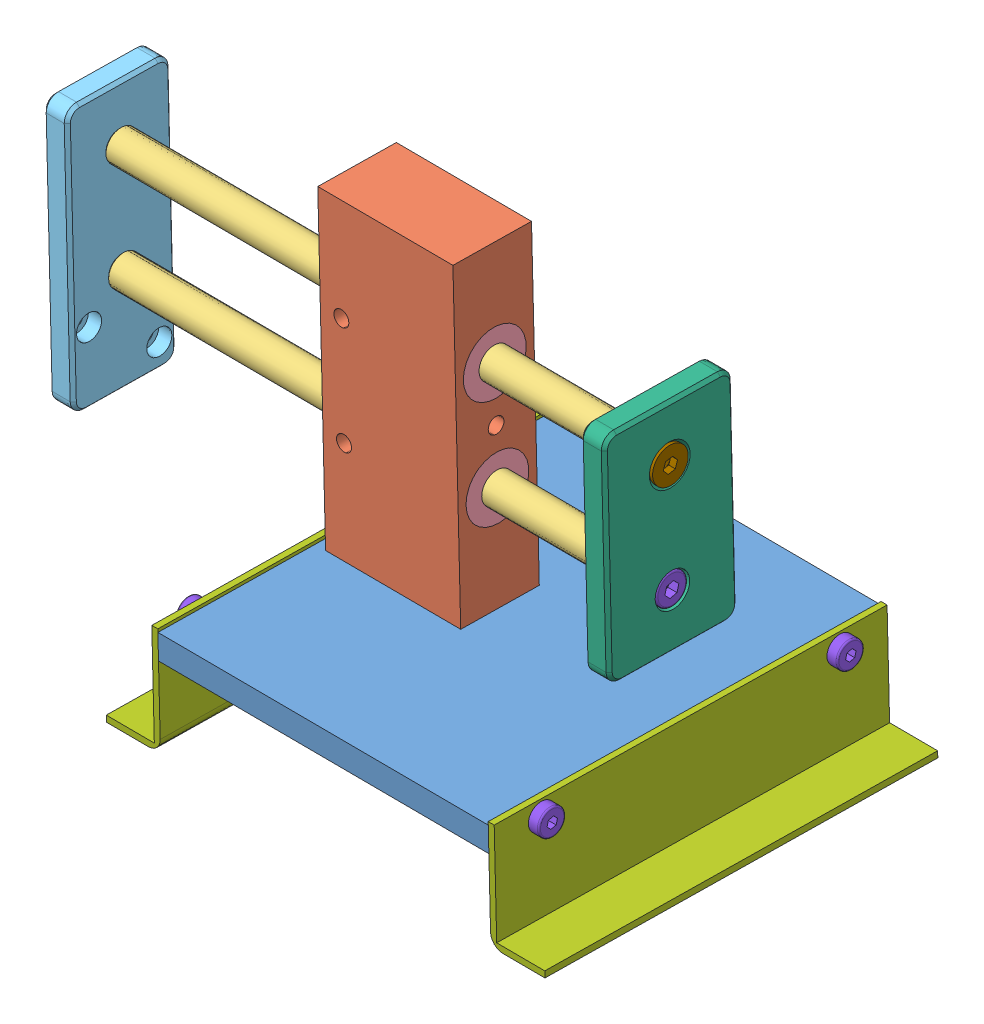
SolidWorks assembly cum s1, configuration Default. Lengths in mm.
Overall size (216.07 137.7 128.52).
22 component instances, 9 part files, 48 mates.
Components (placement in the parent):
- tam de lon-1: tam de lon [Default] at (119.0958 51.1975 54.0073) x (-0.999587 -0.017639 -0.022689) z (-0.022562 -0.007384 0.999718) size (110 8 125)
- con truot s1-2: con truot s1 [Default] at (88.5768 136.6703 53.9498) x (0.999587 0.017639 0.022689) z (0.022562 0.007384 -0.999718) size (45 102 25)
- chot dan huong-1: chot dan huong [Default] at (-13.3094 117.3701 51.5078) x (0.021471 -0.983136 -0.181614) z (-0.019103 -0.182026 0.983108) size (10 175 10)
- chot dan huong-2: chot dan huong [Default] at (-12.6864 82.3765 51.2634) x (0.026236 -0.237789 -0.970963) z (0.011731 -0.971157 0.238153) size (10 175 10)
- bac lot-1: bac lot [Default] at (66.3976 118.7766 53.3171) x (0.028076 -0.767933 -0.639915) z (-0.006137 -0.640287 0.768111) size (20 12 20)
- bac lot-2: bac lot [Default] at (67.0207 83.783 53.0727) x (0.018145 -0.999587 -0.022287) z (-0.022287 -0.022689 0.999494) size (20 12 20)
- bac lot-3: bac lot [Default] at (111.379 119.5704 54.3381) x (-0.014484 -0.372719 0.927831) z (0.024823 -0.927776 -0.37231) size (20 12 20)
- bac lot-4: bac lot [Default] at (112.0021 84.5768 54.0937) x (-0.014484 -0.372719 0.927831) z (0.024823 -0.927776 -0.37231) size (20 12 20)
- ban canh truoc-1: ban canh truoc [Default] at (-12.8555 91.8747 51.3298) x (-0.022562 -0.007384 0.999718) z (0.017801 -0.999817 -0.006983) size (33 8 86)
- ban canh sau -S1-1: ban canh sau -S1 [Default] at (161.9298 102.9601 55.3563) x (-0.022562 -0.007384 0.999718) z (-0.017801 0.999817 0.006983) size (41 8 70)
- khoi do-1: khoi do [Default] at (173.7917 36.5109 117.6508) x (0.022562 0.007384 -0.999718) z (-0.999587 -0.017639 -0.022689) size (125 35 18)
- khoi do-2: khoi do [Default] at (64.9414 35.4633 -9.8487) x (-0.022562 -0.007384 0.999718) z (0.999587 0.017639 0.022689) size (125 35 18)
- socket head thin cap screw_din-2: socket head thin cap screw_din [DIN 7984 - M5 x 12 --- 9.6N] at (57.6203 45.7804 100.0932) x (0.999587 0.017639 0.022689) z (-0.022689 -0.0002 0.999743) size (15.5 8.5 8.5)
- socket head thin cap screw_din-3: socket head thin cap screw_din [DIN 7984 - M5 x 12 --- 9.6N] at (59.7637 46.4818 5.12) x (0.999587 0.017639 0.022689) z (-0.022689 -0.0002 0.999743) size (15.5 8.5 8.5)
- socket head thin cap screw_din-4: socket head thin cap screw_din [DIN 7984 - M5 x 12 --- 9.6N] at (180.7137 48.6161 7.8654) x (-0.999587 -0.017639 -0.022689) z (0.022689 -0.968916 -0.246346) size (15.5 8.5 8.5)
- socket head thin cap screw_din-5: socket head thin cap screw_din [DIN 7984 - M5 x 12 --- 9.6N] at (178.5703 47.9147 102.8386) x (-0.999587 -0.017639 -0.022689) z (0.022689 -0.968916 -0.246346) size (15.5 8.5 8.5)
- socket head thin cap screw_din-6: socket head thin cap screw_din [DIN 7984 - M5 x 12 --- 9.6N] at (108.0343 45.1492 61.2151) x (-0.017801 0.999817 0.006983) z (-0.006983 -0.007108 0.99995) size (15.5 8.5 8.5)
- socket head thin cap screw_din-7: socket head thin cap screw_din [DIN 7984 - M5 x 12 --- 9.6N] at (72.3876 44.6249 45.4025) x (-0.017801 0.999817 0.006983) z (-0.006983 -0.007108 0.99995) size (15.5 8.5 8.5)
- socket head thin cap screw_din-9: socket head thin cap screw_din [DIN 7984 - M6 x 14 --- 11N] at (170.0381 85.6009 55.411) x (-0.999587 -0.017639 -0.022689) z (0.022689 -0.968916 -0.246346) size (18 10 10)
- socket head thin cap screw_din-10: socket head thin cap screw_din [DIN 7984 - M6 x 14 --- 11N] at (-20.4831 82.2389 51.0864) x (0.999587 0.017639 0.022689) z (-0.022689 -0.0002 0.999743) size (18 10 10)
- socket csink head cap screw 10642_din-2: socket csink head cap screw 10642_din [EN ISO 10642 - M6 x 16 - 16N] at (-21.526 117.2251 51.3213) x (0.999587 0.017639 0.022689) z (-0.022678 -0.000819 0.999742) size (16 11.34 11.34)
- socket csink head cap screw 10642_din-3: socket csink head cap screw 10642_din [EN ISO 10642 - M6 x 16 - 16N] at (169.8349 120.6019 55.665) x (-0.999587 -0.017639 -0.022689) z (0.021761 -0.980227 -0.196676) size (16 11.34 11.34)
Mates (geometry in assembly coordinates):
- Parallel5: parallel anti-aligned: plane of tam de lon-1 through (119.0958 51.1975 54.0073) normal (-0.017801 0.999817 0.006983); plane of con truot s1-2 through (90.1077 50.686 53.3493) normal (0.017801 -0.999817 -0.006983)
- Parallel6: parallel anti-aligned: plane of tam de lon-1 through (172.8053 43.7076 117.6817) normal (-0.022562 -0.007384 0.999718); plane of con truot s1-2 through (67.6142 66.3785 40.454) normal (0.022562 0.007384 -0.999718)
- Concentric3: concentric aligned: cylinder of tam de lon-1 through (72.2844 50.4239 45.443) axis (0.017801 -0.999817 -0.006983) radius 2.75; circle of con truot s1-2
- Coincident1: coincident anti-aligned: plane of tam de lon-1 through (119.0958 51.1975 54.0073) normal (-0.017801 0.999817 0.006983); plane of con truot s1-2 through (90.1077 50.686 53.3493) normal (0.017801 -0.999817 -0.006983)
- Concentric4: concentric anti-aligned: cylinder of con truot s1-2 through (41.408 118.3356 52.7498) axis (0.999587 0.017639 0.022689) radius 6; cylinder of chot dan huong-1 through (259.5778 122.1855 57.702) axis (-0.999587 -0.017639 -0.022689) radius 5
- Concentric5: concentric anti-aligned: cylinder of con truot s1-2 through (42.031 83.342 52.5054) axis (0.999587 0.017639 0.022689) radius 6; cylinder of chot dan huong-2 through (260.2009 87.1919 57.4576) axis (-0.999587 -0.017639 -0.022689) radius 5
- Concentric6: concentric anti-aligned: cylinder of con truot s1-2 through (41.408 118.3356 52.7498) axis (0.999587 0.017639 0.022689) radius 6; cylinder of bac lot-1 through (78.3927 118.9883 53.5893) axis (-0.999587 -0.017639 -0.022689) radius 6
- Coincident2: coincident anti-aligned: plane of con truot s1-2 through (68.3968 118.8119 53.3624) normal (-0.999587 -0.017639 -0.022689); plane of bac lot-1 through (68.3968 118.8119 53.3624) normal (0.999587 0.017639 0.022689)
- Concentric7: concentric anti-aligned: cylinder of con truot s1-2 through (42.031 83.342 52.5054) axis (0.999587 0.017639 0.022689) radius 6; cylinder of bac lot-2 through (79.0157 83.9947 53.3449) axis (-0.999587 -0.017639 -0.022689) radius 6
- Coincident3: coincident anti-aligned: plane of con truot s1-2 through (69.0199 83.8183 53.1181) normal (-0.999587 -0.017639 -0.022689); plane of bac lot-2 through (69.0199 83.8183 53.1181) normal (0.999587 0.017639 0.022689)
- Concentric8: concentric aligned: cylinder of con truot s1-2 through (41.408 118.3356 52.7498) axis (0.999587 0.017639 0.022689) radius 6; cylinder of bac lot-3 through (99.384 119.3587 54.0658) axis (0.999587 0.017639 0.022689) radius 6
- Coincident4: coincident anti-aligned: plane of con truot s1-2 through (109.3799 119.5351 54.2927) normal (0.999587 0.017639 0.022689); plane of bac lot-3 through (109.3799 119.5351 54.2927) normal (-0.999587 -0.017639 -0.022689)
- Concentric9: concentric aligned: cylinder of con truot s1-2 through (42.031 83.342 52.5054) axis (0.999587 0.017639 0.022689) radius 6; cylinder of bac lot-4 through (100.0071 84.3651 53.8214) axis (0.999587 0.017639 0.022689) radius 6
- Coincident5: coincident anti-aligned: plane of con truot s1-2 through (110.0029 84.5415 54.0483) normal (0.999587 0.017639 0.022689); plane of bac lot-4 through (110.0029 84.5415 54.0483) normal (-0.999587 -0.017639 -0.022689)
- Concentric10: concentric aligned: cylinder of chot dan huong-1 through (259.5778 122.1855 57.702) axis (-0.999587 -0.017639 -0.022689) radius 5; cylinder of ban canh truoc-1 through (-13.3094 117.3701 51.5078) axis (-0.999587 -0.017639 -0.022689) radius 3.3
- Concentric11: concentric aligned: cylinder of chot dan huong-2 through (260.2009 87.1919 57.4576) axis (-0.999587 -0.017639 -0.022689) radius 5; cylinder of ban canh truoc-1 through (-12.6864 82.3765 51.2634) axis (-0.999587 -0.017639 -0.022689) radius 3.3
- Coincident6: coincident anti-aligned: plane of chot dan huong-1 through (-13.3094 117.3701 51.5078) normal (-0.999587 -0.017639 -0.022689); plane of ban canh truoc-1 through (-12.8555 91.8747 51.3298) normal (0.999587 0.017639 0.022689)
- Coincident7: coincident anti-aligned: plane of chot dan huong-2 through (-12.6864 82.3765 51.2634) normal (-0.999587 -0.017639 -0.022689); plane of ban canh truoc-1 through (-12.8555 91.8747 51.3298) normal (0.999587 0.017639 0.022689)
- Concentric12: concentric anti-aligned: cylinder of chot dan huong-1 through (259.5778 122.1855 57.702) axis (-0.999587 -0.017639 -0.022689) radius 5; cylinder of ban canh sau -S1-1 through (161.6183 120.4569 55.4785) axis (0.999587 0.017639 0.022689) radius 3.3
- Concentric13: concentric anti-aligned: cylinder of chot dan huong-2 through (260.2009 87.1919 57.4576) axis (-0.999587 -0.017639 -0.022689) radius 5; cylinder of ban canh sau -S1-1 through (162.2414 85.4633 55.2341) axis (0.999587 0.017639 0.022689) radius 3.3
- Coincident8: coincident anti-aligned: plane of chot dan huong-1 through (161.6183 120.4569 55.4785) normal (0.999587 0.017639 0.022689); plane of ban canh sau -S1-1 through (161.9298 102.9601 55.3563) normal (-0.999587 -0.017639 -0.022689)
- Coincident9: coincident anti-aligned: plane of chot dan huong-2 through (162.2414 85.4633 55.2341) normal (0.999587 0.017639 0.022689); plane of ban canh sau -S1-1 through (161.9298 102.9601 55.3563) normal (-0.999587 -0.017639 -0.022689)
- Parallel7: parallel aligned: plane of tam de lon-1 through (65.671 42.6903 -9.7789) normal (-0.999587 -0.017639 -0.022689); plane of khoi do-1 through (176.0884 18.6354 -7.4646) normal (-0.999587 -0.017639 -0.022689)
- Parallel8: parallel aligned: plane of tam de lon-1 through (119.0958 51.1975 54.0073) normal (-0.017801 0.999817 0.006983); plane of khoi do-1 through (175.4654 53.629 -7.2202) normal (-0.017801 0.999817 0.006983)
- Concentric14: concentric aligned: cylinder of tam de lon-1 through (160.2221 48.2545 7.4003) axis (0.999587 0.017639 0.022689) radius 2.5; cylinder of khoi do-1 through (52.2667 46.3495 4.9498) axis (0.999587 0.017639 0.022689) radius 2.5
- Coincident10: coincident anti-aligned: plane of tam de lon-1 through (175.6256 44.6306 -7.2831) normal (0.999587 0.017639 0.022689); plane of khoi do-1 through (176.0884 18.6354 -7.4646) normal (-0.999587 -0.017639 -0.022689)
- Parallel9: parallel anti-aligned: plane of tam de lon-1 through (65.671 42.6903 -9.7789) normal (-0.999587 -0.017639 -0.022689); plane of khoi do-2 through (63.3136 15.7721 115.0043) normal (0.999587 0.017639 0.022689)
- Parallel10: parallel anti-aligned: plane of tam de lon-1 through (119.0958 51.1975 54.0073) normal (-0.017801 0.999817 0.006983); plane of khoi do-2 through (63.3136 15.7721 115.0043) normal (0.017801 -0.999817 -0.006983)
- Concentric15: concentric aligned: cylinder of tam de lon-1 through (80.2552 46.8434 5.5851) axis (-0.999587 -0.017639 -0.022689) radius 2.5; cylinder of khoi do-2 through (188.2106 48.7484 8.0356) axis (-0.999587 -0.017639 -0.022689) radius 2.5
- Coincident11: coincident anti-aligned: plane of tam de lon-1 through (65.671 42.6903 -9.7789) normal (-0.999587 -0.017639 -0.022689); plane of khoi do-2 through (63.3136 15.7721 115.0043) normal (0.999587 0.017639 0.022689)
- Concentric16: concentric aligned: cylinder of khoi do-2 through (186.0672 48.047 103.0088) axis (-0.999587 -0.017639 -0.022689) radius 2.5; cylinder of socket head thin cap screw_din-2 through (25.8834 45.2204 99.3728) axis (-0.999587 -0.017639 -0.022689) radius 4.25
- Coincident12: coincident anti-aligned: plane of khoi do-2 through (61.2788 17.7365 114.9729) normal (-0.999587 -0.017639 -0.022689); plane of socket head thin cap screw_din-2 through (61.0438 50.0915 100.1718) normal (0.999587 0.017639 0.022689)
- Concentric17: concentric aligned: cylinder of khoi do-2 through (188.2106 48.7484 8.0356) axis (-0.999587 -0.017639 -0.022689) radius 2.5; cylinder of socket head thin cap screw_din-3 through (28.0268 45.9218 4.3996) axis (-0.999587 -0.017639 -0.022689) radius 4.25
- Coincident13: coincident anti-aligned: plane of khoi do-2 through (61.2788 17.7365 114.9729) normal (-0.999587 -0.017639 -0.022689); plane of socket head thin cap screw_din-3 through (63.1872 50.7929 5.1986) normal (0.999587 0.017639 0.022689)
- Concentric18: concentric aligned: cylinder of khoi do-1 through (52.2667 46.3495 4.9498) axis (0.999587 0.017639 0.022689) radius 2.5; cylinder of socket head thin cap screw_din-4 through (212.4506 49.1762 8.5858) axis (0.999587 0.017639 0.022689) radius 4.25
- Coincident14: coincident anti-aligned: plane of khoi do-1 through (178.052 20.6703 -7.4053) normal (0.999587 0.017639 0.022689); plane of socket head thin cap screw_din-4 through (177.2901 49.6031 3.6681) normal (-0.999587 -0.017639 -0.022689)
- Concentric19: concentric aligned: cylinder of khoi do-1 through (50.1234 45.6481 99.9231) axis (0.999587 0.017639 0.022689) radius 2.5; cylinder of socket head thin cap screw_din-5 through (210.3072 48.4747 103.559) axis (0.999587 0.017639 0.022689) radius 4.25
- Coincident15: coincident anti-aligned: plane of khoi do-1 through (178.052 20.6703 -7.4053) normal (0.999587 0.017639 0.022689); plane of socket head thin cap screw_din-5 through (175.1467 48.9017 98.6413) normal (-0.999587 -0.017639 -0.022689)
- Concentric20: concentric aligned: cylinder of tam de lon-1 through (107.972 48.6485 61.2395) axis (0.017801 -0.999817 -0.006983) radius 5; cylinder of socket head thin cap screw_din-6 through (108.5995 13.405 60.9934) axis (0.017801 -0.999817 -0.006983) radius 4.25
- Coincident16: coincident anti-aligned: plane of tam de lon-1 through (107.972 48.6485 61.2395) normal (0.017801 -0.999817 -0.006983); plane of socket head thin cap screw_din-6 through (103.7228 48.5731 61.2093) normal (-0.017801 0.999817 0.006983)
- Concentric21: concentric aligned: cylinder of tam de lon-1 through (72.2844 50.4239 45.443) axis (0.017801 -0.999817 -0.006983) radius 2.75; cylinder of socket head thin cap screw_din-7 through (72.9528 12.8807 45.1808) axis (0.017801 -0.999817 -0.006983) radius 4.25
- Coincident17: coincident anti-aligned: plane of tam de lon-1 through (72.3253 48.1243 45.4269) normal (0.017801 -0.999817 -0.006983); plane of socket head thin cap screw_din-7 through (68.0761 48.0489 45.3967) normal (-0.017801 0.999817 0.006983)
- Concentric22: concentric aligned: cylinder of ban canh sau -S1-1 through (166.0398 85.5303 55.3203) axis (0.999587 0.017639 0.022689) radius 5.5; cylinder of socket head thin cap screw_din-9 through (201.775 86.1609 56.1314) axis (0.999587 0.017639 0.022689) radius 5
- Coincident18: coincident anti-aligned: plane of ban canh sau -S1-1 through (166.0398 85.5303 55.3203) normal (0.999587 0.017639 0.022689); plane of socket head thin cap screw_din-9 through (166.128 86.7641 50.4757) normal (-0.999587 -0.017639 -0.022689)
- Concentric23: concentric aligned: cylinder of ban canh truoc-1 through (-16.4848 82.3095 51.1772) axis (-0.999587 -0.017639 -0.022689) radius 5.5; cylinder of socket head thin cap screw_din-10 through (-52.22 81.6789 50.3661) axis (-0.999587 -0.017639 -0.022689) radius 5
- Coincident19: coincident anti-aligned: plane of ban canh truoc-1 through (-16.4848 82.3095 51.1772) normal (-0.999587 -0.017639 -0.022689); plane of socket head thin cap screw_din-10 through (-16.573 87.3087 51.1762) normal (0.999587 0.017639 0.022689)
- Coincident20: coincident aligned: cone of ban canh truoc-1 through (-18.1074 117.2854 51.3989) axis (0.999587 0.017639 0.022689); cone of socket csink head cap screw 10642_din-2 through (-20.4764 117.2436 51.3451) axis (0.999587 0.017639 0.022689)
- Coincident21: coincident aligned: cone of ban canh sau -S1-1 through (166.4163 120.5415 55.5874) axis (-0.999587 -0.017639 -0.022689); cone of socket csink head cap screw 10642_din-3 through (168.7854 120.5833 55.6411) axis (-0.999587 -0.017639 -0.022689)
